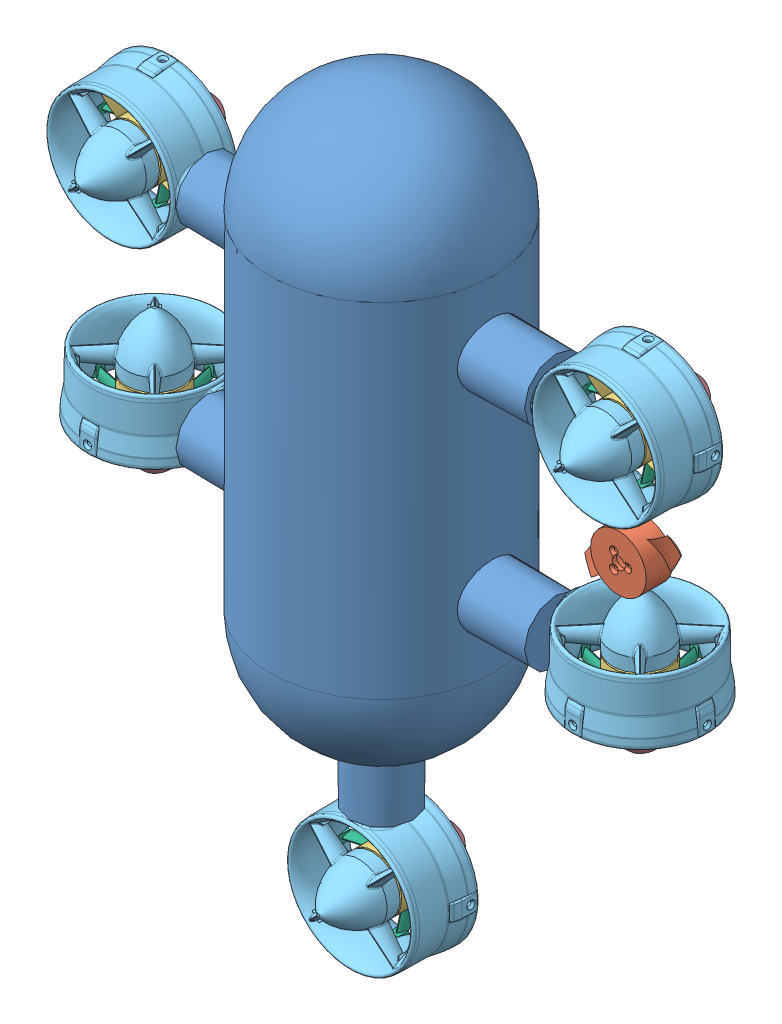
SolidWorks assembly ROV Horizontal model, configuration Default. Lengths in mm.
Overall size (444.61 543.96 160).
37 component instances, 7 part files, 14 mates.
Components (placement in the parent):
- ROV proposed changes-1: ROV proposed changes [Default] at (132.9369 205.6544 359.7323) size (250 446.66 160)
- T100-THRUSTER-R1 v6.step-1: T100-THRUSTER-R1 v6.step [Default] at (306.9369 279.905 358.436) x (0 -1 0) z (0 0 -1) size (157.85 97.3 100.86)
  - T100-THRUSTER-R1_1.step-1: T100-THRUSTER-R1_1.step [Default] at origin size (157.85 97.3 100.86)
    - Prop (Rev).step-1: Prop (Rev).step [Default] at origin size (59 69.35 19.07) (hidden)
    - Prop.step-1: Prop.step [Default] at origin size (58.99 69.35 19.07)
    - Back.step-1: Back.step [Default] at origin size (40 40 25.4)
    - Main.step-1: Main.step [Default] at origin size (96.61 97.3 67.18)
    - Support.step-1: Support.step [Default] at origin size (87.65 87.65 22.12)
- watec902H-1: watec902H [Default] at (132.9369 337.0844 359.7323) x (0.719113 0 -0.694893) z (0 1 0) size (46.8 36.5 58.1)
- T100-THRUSTER-R1 v6.step-2: T100-THRUSTER-R1 v6.step [Default] at (306.9369 131.4136 348.3864) x (0 0 1) z (0 -1 0) size (157.85 97.3 100.86)
  - T100-THRUSTER-R1_1.step-1: T100-THRUSTER-R1_1.step [Default] at origin size (157.85 97.3 100.86)
    - Prop (Rev).step-1: Prop (Rev).step [Default] at origin size (59 69.35 19.07) (hidden)
    - Prop.step-1: Prop.step [Default] at origin size (58.99 69.35 19.07)
    - Back.step-1: Back.step [Default] at origin size (40 40 25.4)
    - Main.step-1: Main.step [Default] at origin size (96.61 97.3 67.18)
    - Support.step-1: Support.step [Default] at origin size (87.65 87.65 22.12)
- T100-THRUSTER-R1 v6.step-3: T100-THRUSTER-R1 v6.step [Default] at (131.5693 -86.6756 358.436) x (-1 0 0) z (0 0 -1) size (157.85 97.3 100.86)
  - T100-THRUSTER-R1_1.step-1: T100-THRUSTER-R1_1.step [Default] at origin size (157.85 97.3 100.86)
    - Prop (Rev).step-1: Prop (Rev).step [Default] at origin size (59 69.35 19.07) (hidden)
    - Prop.step-1: Prop.step [Default] at origin size (58.99 69.35 19.07)
    - Back.step-1: Back.step [Default] at origin size (40 40 25.4)
    - Main.step-1: Main.step [Default] at origin size (96.61 97.3 67.18)
    - Support.step-1: Support.step [Default] at origin size (87.65 87.65 22.12)
- T100-THRUSTER-R1 v6.step-4: T100-THRUSTER-R1 v6.step [Default] at (-41.0631 279.905 358.436) x (0 1 0) z (0 0 -1) size (157.85 97.3 100.86)
  - T100-THRUSTER-R1_1.step-1: T100-THRUSTER-R1_1.step [Default] at origin size (157.85 97.3 100.86)
    - Prop (Rev).step-1: Prop (Rev).step [Default] at origin size (59 69.35 19.07) (hidden)
    - Prop.step-1: Prop.step [Default] at origin size (58.99 69.35 19.07)
    - Back.step-1: Back.step [Default] at origin size (40 40 25.4)
    - Main.step-1: Main.step [Default] at origin size (96.61 97.3 67.18)
    - Support.step-1: Support.step [Default] at origin size (87.65 87.65 22.12)
- T100-THRUSTER-R1 v6.step-5: T100-THRUSTER-R1 v6.step [Default] at (-41.0631 131.4136 348.3864) x (0 0 -1) z (0 -1 0) size (157.85 97.3 100.86)
  - T100-THRUSTER-R1_1.step-1: T100-THRUSTER-R1_1.step [Default] at origin size (157.85 97.3 100.86)
    - Prop (Rev).step-1: Prop (Rev).step [Default] at origin size (59 69.35 19.07) (hidden)
    - Prop.step-1: Prop.step [Default] at origin size (58.99 69.35 19.07)
    - Back.step-1: Back.step [Default] at origin size (40 40 25.4)
    - Main.step-1: Main.step [Default] at origin size (96.61 97.3 67.18)
    - Support.step-1: Support.step [Default] at origin size (87.65 87.65 22.12)
Mates (geometry in assembly coordinates):
- Coincident3: coincident anti-aligned: line of ROV proposed changes-1 through (132.9369 280.9844 359.7323) axis (0 1 0); line of watec902H-1 through (132.9369 382.0844 359.7323) axis (0 -1 0)
- Coincident6: coincident anti-aligned: plane of ROV proposed changes-1 through (132.9369 328.9844 359.7323) normal (0 1 0); plane of watec902H-1 through (125.7993 328.9844 355.2961) normal (0 -1 0)
- Coincident17: coincident aligned: plane of T100-THRUSTER-R1 v6.step-2/T100-THRUSTER-R1_1.step-1/Main.step-1 through (304.4369 176.6927 300.0325) normal (0 1 0); plane of T100-THRUSTER-R1 v6.step-5/T100-THRUSTER-R1_1.step-1/Main.step-1 through (-38.5631 176.6927 396.7403) normal (0 1 0)
- Coincident18: coincident aligned: plane of T100-THRUSTER-R1 v6.step-1/T100-THRUSTER-R1_1.step-1/Main.step-1 through (304.4369 328.2588 403.715) normal (0 0 1); plane of T100-THRUSTER-R1 v6.step-4/T100-THRUSTER-R1_1.step-1/Main.step-1 through (-38.5631 231.5511 403.715) normal (0 0 1)
- Coincident19: coincident aligned: plane of T100-THRUSTER-R1 v6.step-1/T100-THRUSTER-R1_1.step-1/Main.step-1 through (304.4369 328.2588 403.715) normal (0 0 1); plane of T100-THRUSTER-R1 v6.step-3/T100-THRUSTER-R1_1.step-1/Main.step-1 through (179.9232 -84.1756 403.715) normal (0 0 1)
- Parallel1: parallel aligned: plane of ROV proposed changes-1 through (132.9369 328.9844 359.7323) normal (0 1 0); plane of T100-THRUSTER-R1 v6.step-2/T100-THRUSTER-R1_1.step-1/Main.step-1 through (304.4369 176.6927 300.0325) normal (0 1 0)
- Perpendicular1: perpendicular: plane of T100-THRUSTER-R1 v6.step-1/T100-THRUSTER-R1_1.step-1/Main.step-1 through (304.4369 328.2588 403.715) normal (0 0 1); plane of T100-THRUSTER-R1 v6.step-2/T100-THRUSTER-R1_1.step-1/Main.step-1 through (304.4369 176.6927 300.0325) normal (0 1 0)
- Coincident22: coincident anti-aligned: plane of ROV proposed changes-1 through (257.9369 130.6544 359.7323) normal (1 0 0); plane of T100-THRUSTER-R1 v6.step-2/T100-THRUSTER-R1_1.step-1/Main.step-1 through (257.9369 136.6654 348.3864) normal (-1 0 0)
- Coincident23: coincident anti-aligned: plane of ROV proposed changes-1 through (257.9369 280.6544 359.7323) normal (1 0 0); plane of T100-THRUSTER-R1 v6.step-1/T100-THRUSTER-R1_1.step-1/Main.step-1 through (257.9369 279.905 363.6877) normal (-1 0 0)
- Coincident24: coincident anti-aligned: plane of ROV proposed changes-1 through (7.9369 280.6544 359.7323) normal (-1 0 0); plane of T100-THRUSTER-R1 v6.step-4/T100-THRUSTER-R1_1.step-1/Main.step-1 through (7.9369 279.905 363.6877) normal (1 0 0)
- Coincident25: coincident anti-aligned: plane of ROV proposed changes-1 through (7.9369 130.6544 359.7323) normal (-1 0 0); plane of T100-THRUSTER-R1 v6.step-5/T100-THRUSTER-R1_1.step-1/Main.step-1 through (7.9369 136.6654 348.3864) normal (1 0 0)
- Coincident26: coincident anti-aligned: plane of ROV proposed changes-1 through (132.9369 -37.6756 359.7323) normal (0 -1 0); plane of T100-THRUSTER-R1 v6.step-3/T100-THRUSTER-R1_1.step-1/Main.step-1 through (131.5693 -37.6756 363.6877) normal (0 1 0)
- Concentric1: concentric anti-aligned: cylinder of T100-THRUSTER-R1 v6.step-2/T100-THRUSTER-R1_1.step-1/Support.step-1 through (350.6246 115.5419 348.3864) axis (-1 0 0) radius 1.25; cylinder of T100-THRUSTER-R1 v6.step-5/T100-THRUSTER-R1_1.step-1/Main.step-1 through (-89.3391 115.5419 348.3864) axis (1 0 0) radius 1.6
- Concentric2: concentric anti-aligned: cylinder of T100-THRUSTER-R1 v6.step-1/T100-THRUSTER-R1_1.step-1/Support.step-1 through (350.6246 279.905 342.5643) axis (-1 0 0) radius 1.25; cylinder of T100-THRUSTER-R1 v6.step-4/T100-THRUSTER-R1_1.step-1/Support.step-1 through (-84.7509 279.905 342.5643) axis (1 0 0) radius 1.25
